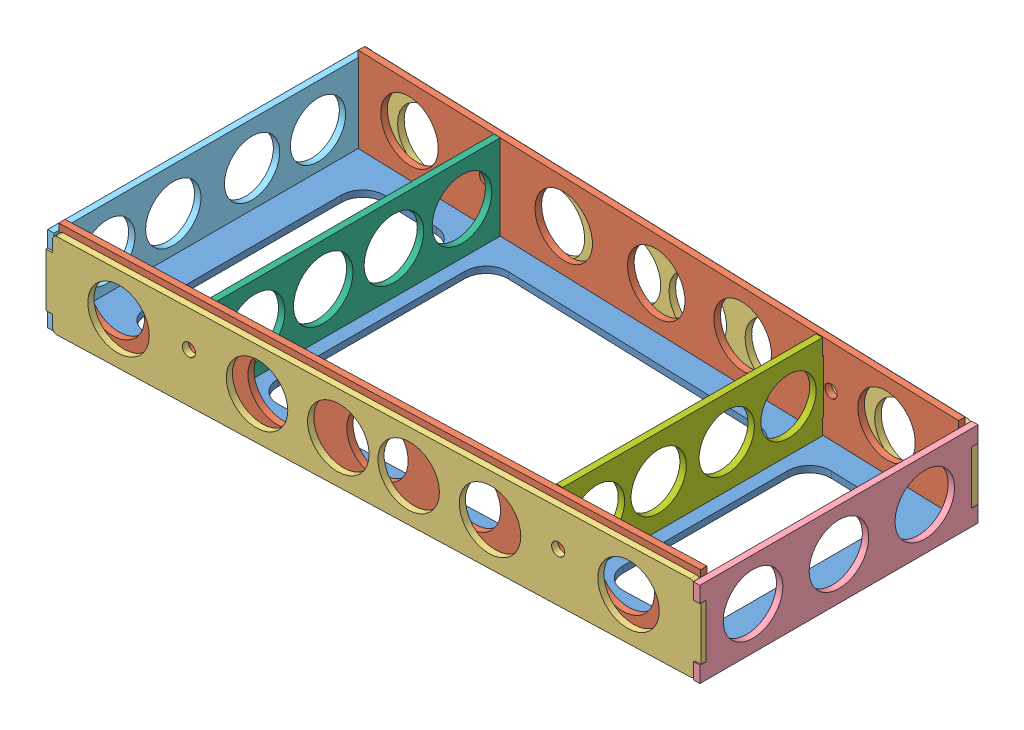
SolidWorks assembly wingmount_wood, configuration Default. Lengths in mm.
Overall size (298 43 149.93).
9 component instances, 7 part files, 24 mates.
Components (placement in the parent):
- wingmount_top-1: wingmount_top [Default] at (-3.188 185.376 268.8315) size (292 3 143.59)
- wingmount_rib-1: wingmount_rib [Default] at (288.5624 188.376 327.9681) x (0.033321 0 0.999445) z (0.999445 0 -0.033321) size (3 43 292)
- wingmount_rib-2: wingmount_rib [Default] at (288.6624 188.376 206.6965) x (-0.033321 0 0.999445) z (0.999445 0 0.033321) size (3 43 292)
- wingmount_fuse-1: wingmount_fuse [Default] at (288.7623 185.376 203.6982) x (-0.033321 0 0.999445) z (0.999445 0 0.033321) size (3 40 298)
- wingmount_fuse-2: wingmount_fuse [Default] at (-3.0755 185.376 343.6944) x (-0.033321 0 -0.999445) z (-0.999445 0 0.033321) size (3 40 298)
- wingmountfuse_aft-1: wingmountfuse_aft [Default] at (288.812 225.376 334.4965) x (0 0 -1) z (1 0 0) size (130.7 40 3)
- wingmountfuse_nose-1: wingmountfuse_nose [Default] at (-6.188 205.376 268.3669) size (3 40 149)
- wingmount_nose-1: wingmount_nose [Default] at (65.812 208.376 268.8315) x (-1 0 0) z (0 0 1) size (3 43 139.2)
- wingmount_aft-1: wingmount_aft [Default] at (219.812 208.376 268.8315) x (0 0 1) z (1 0 0) size (128 43 3)
Mates (geometry in assembly coordinates):
- Coincident1: coincident aligned: plane of wingmount_top-1 through (288.812 188.376 330.9615) normal (0.033321 0 0.999445); plane of wingmount_rib-1 through (288.6624 188.376 330.9665) normal (0.033321 0 0.999445)
- Coincident2: coincident aligned: plane of wingmount_top-1 through (-3.188 185.376 268.8315) normal (0 -1 0); plane of wingmount_rib-1 through (288.6624 185.376 330.9665) normal (0 -1 0)
- Coincident5: coincident: line of wingmount_top-1 through (19.312 185.376 339.9464) axis (0 0 -1); point of wingmount_rib-1
- Coincident6: coincident aligned: plane of wingmount_top-1 through (-3.188 188.376 196.9665) normal (0.033321 0 -0.999445); plane of wingmount_rib-2 through (288.6624 188.376 206.6965) normal (0.033321 0 -0.999445)
- Coincident7: coincident aligned: plane of wingmount_top-1 through (-3.188 185.376 268.8315) normal (0 -1 0); plane of wingmount_rib-2 through (288.5624 185.376 209.6948) normal (0 -1 0)
- Coincident8: coincident: point of wingmount_top-1; line of wingmount_rib-2 through (19.2121 185.376 200.715) axis (0.033321 0 -0.999445)
- Coincident10: coincident anti-aligned: plane of wingmount_rib-2 through (288.6624 188.376 206.6965) normal (0.033321 0 -0.999445); plane of wingmount_fuse-1 through (288.6624 185.376 206.6965) normal (-0.033321 0 0.999445)
- Concentric3: concentric anti-aligned: cylinder of wingmount_rib-2 through (59.0233 208.376 192.0367) axis (-0.033321 0 0.999445) radius 3; cylinder of wingmount_fuse-1 through (58.7901 208.376 199.0328) axis (0.033321 0 -0.999445) radius 3
- Concentric4: concentric anti-aligned: cylinder of wingmount_rib-2 through (226.9301 208.376 197.6345) axis (-0.033321 0 0.999445) radius 3; cylinder of wingmount_fuse-1 through (226.6968 208.376 204.6306) axis (0.033321 0 -0.999445) radius 3
- Coincident12: coincident anti-aligned: plane of wingmount_rib-1 through (288.6624 188.376 330.9665) normal (0.033321 0 0.999445); plane of wingmount_fuse-2 through (-3.1755 185.376 340.6961) normal (-0.033321 0 -0.999445)
- Concentric7: concentric aligned: cylinder of wingmount_rib-1 through (58.4569 208.376 328.6358) axis (0.033321 0 0.999445) radius 3; cylinder of wingmount_fuse-2 through (58.7901 208.376 338.6302) axis (0.033321 0 0.999445) radius 3
- Concentric8: concentric aligned: cylinder of wingmount_rib-1 through (226.3636 208.376 323.0379) axis (0.033321 0 0.999445) radius 3; cylinder of wingmount_fuse-2 through (226.6968 208.376 333.0324) axis (0.033321 0 0.999445) radius 3
- Coincident16: coincident anti-aligned: plane of wingmount_top-1 through (288.812 188.376 206.7015) normal (1 0 0); plane of wingmountfuse_aft-1 through (288.812 225.376 334.4965) normal (-1 0 0)
- Coincident19: coincident: line of wingmount_fuse-1 through (291.6607 192.876 206.7965) axis (0 1 0); plane of wingmountfuse_aft-1 through (291.812 225.376 206.7965) normal (0 0 -1)
- Coincident20: coincident: line of wingmount_fuse-1 through (291.7607 192.876 203.7981) axis (-0.033321 0 0.999445); plane of wingmountfuse_aft-1 through (291.812 192.876 334.4965) normal (0 1 0)
- Coincident21: coincident anti-aligned: plane of wingmount_top-1 through (-3.188 188.376 196.9665) normal (-1 0 0); plane of wingmountfuse_nose-1 through (-3.188 205.376 268.3669) normal (1 0 0)
- Coincident22: coincident: line of wingmount_fuse-1 through (-6.1738 217.876 196.8669) axis (0 -1 0); plane of wingmountfuse_nose-1 through (-3.188 205.376 196.8669) normal (0 0 -1)
- Coincident23: coincident: line of wingmount_fuse-1 through (-6.0738 192.876 193.8686) axis (-0.033321 0 0.999445); plane of wingmountfuse_nose-1 through (-3.188 192.876 268.3669) normal (0 1 0)
- Coincident24: coincident anti-aligned: plane of wingmount_top-1 through (-3.188 188.376 268.8315) normal (0 1 0); plane of wingmount_nose-1 through (62.812 188.376 268.8315) normal (0 -1 0)
- Coincident25: coincident aligned: line of wingmount_top-1 through (62.812 185.376 218.8315) axis (1 0 0); line of wingmount_nose-1 through (62.812 185.376 218.8315) axis (1 0 0)
- Coincident26: coincident anti-aligned: line of wingmount_top-1 through (65.812 185.376 218.8315) axis (0 0 1); line of wingmount_nose-1 through (65.812 185.376 243.8315) axis (0 0 -1)
- Coincident27: coincident anti-aligned: plane of wingmount_top-1 through (-3.188 188.376 268.8315) normal (0 1 0); plane of wingmount_aft-1 through (222.812 188.376 268.8315) normal (0 -1 0)
- Coincident28: coincident anti-aligned: line of wingmount_top-1 through (219.812 185.376 243.8315) axis (1 0 0); line of wingmount_aft-1 through (222.812 185.376 243.8315) axis (-1 0 0)
- Coincident29: coincident aligned: line of wingmount_top-1 through (222.812 185.376 218.8315) axis (0 0 1); line of wingmount_aft-1 through (222.812 185.376 218.8315) axis (0 0 1)
